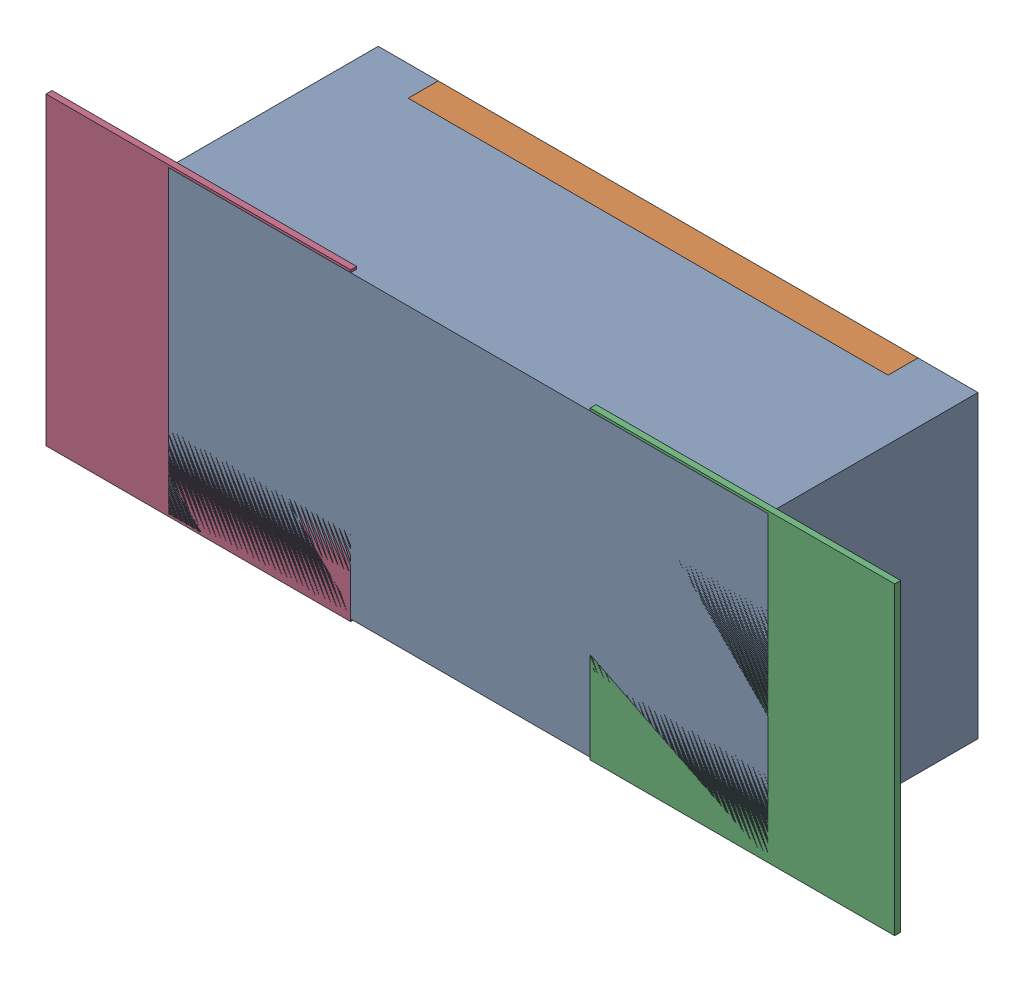
SolidWorks assembly R101, configuration Défaut. Lengths in mm.
Overall size (1.42 0.51 0.35).
5 component instances, 2 part files, 0 mates.
Components (placement in the parent):
- R0402-1: R0402 [Défaut] at (20.7376 -27.2891 -2.0818) x (-1 0 0) z (0 0 -1) size (1 0.5 0.35)
- 6504207776-1: 6504207776 [Défaut] at (21.1947 -27.289 -2.0918) size (0.51 0.51 0.01)
  - Extruded-1: Extruded [Défaut] at origin size (0.51 0.51 0.01)
- 6504207776-2: 6504207776 [Défaut] at (20.2876 -27.289 -2.0918) size (0.51 0.51 0.01)
  - Extruded-1: Extruded [Défaut] at origin size (0.51 0.51 0.01)
